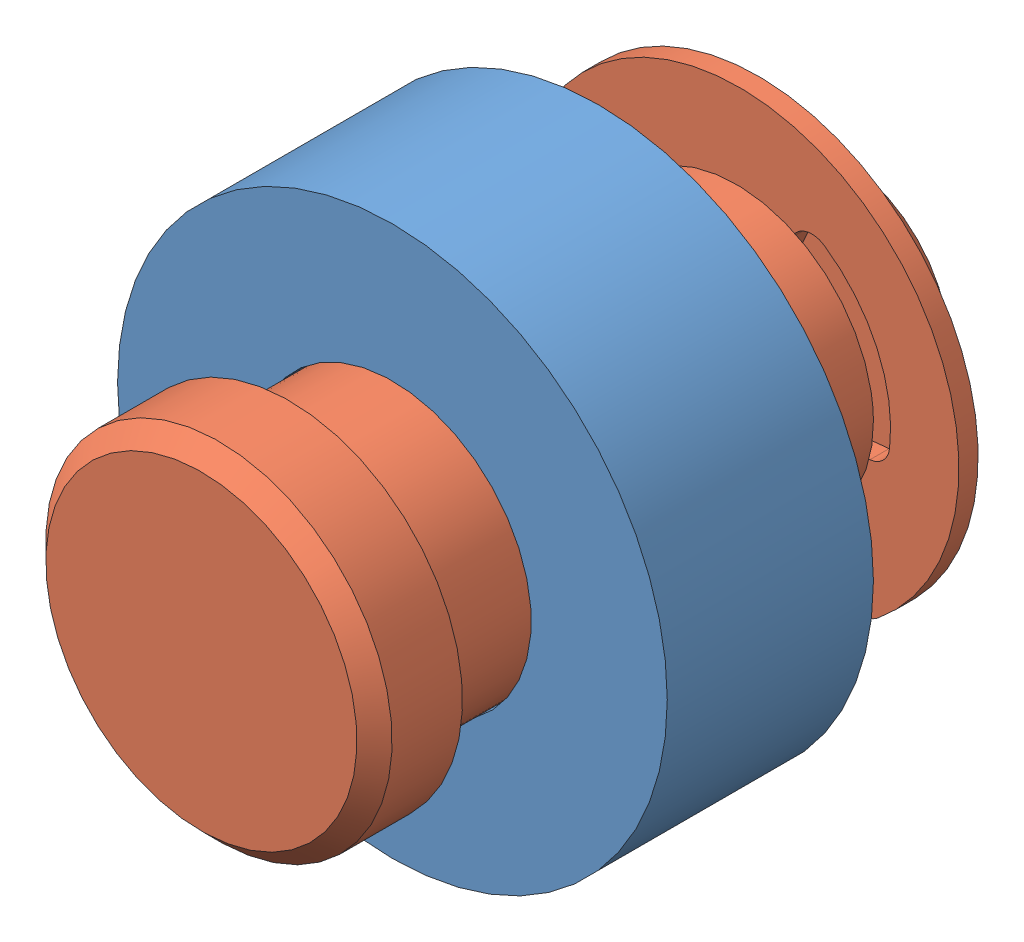
SolidWorks assembly EXK-02-0030, configuration Default. Lengths in mm.
Overall size (25.4 25.4 29.46).
2 component instances, 2 part files, 6 mates.
Components (placement in the parent):
- 92510A817_ALUM UNTHRD SPACER-1: 92510A817_ALUM UNTHRD SPACER [92510A817] at (-28.2457 1.9457 13.5829) size (25.4 25.4 9.53)
- 92735A500_CLEVIS PIN WITH RETAINING RING GROOVE-1: 92735A500_CLEVIS PIN WITH RETAINING RING GROOVE [92735A500] at (-28.2457 1.9457 10.4079) x (0.995255 0.097304 0) z (0 0 1) size (20.32 18.8 29.46)
Mates (geometry in assembly coordinates):
- Concentric1: concentric anti-aligned: cylinder of 92510A817_ALUM UNTHRD SPACER-1 through (-28.2457 1.9457 18.3454) axis (0 0 -1) radius 6.4135; cylinder of EXK-01-0016-1 through (-28.2457 1.9457 4.0579) axis (0 0 1) radius 6.6675
- Width1: width anti-aligned: plane of EXK-01-0016-1 through (-28.2457 1.9457 18.5359) normal (0 0 -1); plane of 92510A817_ALUM UNTHRD SPACER-1 through (-28.2457 1.9457 8.6299) normal (0 0 1); plane of EXK-01-0016-1 through (-28.2457 1.9457 18.3454) normal (0 0 1); plane of 92510A817_ALUM UNTHRD SPACER-1 through (-28.2457 1.9457 8.8204) normal (0 0 -1)
- ProfileCenter1: profile center anti-aligned: circle of EXK-01-0016-1; circle of 92735A500_CLEVIS PIN WITH RETAINING RING GROOVE-1
- ProfileCenter2: profile center aligned: circle of 2867T470_CORROSION-RESISTANT SLEEVE BEARING-1; circle of EXK-01-0016-1
- ProfileCenter3: profile center anti-aligned: circle of 2867T470_CORROSION-RESISTANT SLEEVE BEARING-2; circle of EXK-01-0016-1
- ProfileCenter4: profile center anti-aligned: circle of 92735A430_GROOVED CLEVIS PIN WITH RETAINING RING-1; circle of 2867T470_CORROSION-RESISTANT SLEEVE BEARING-2
